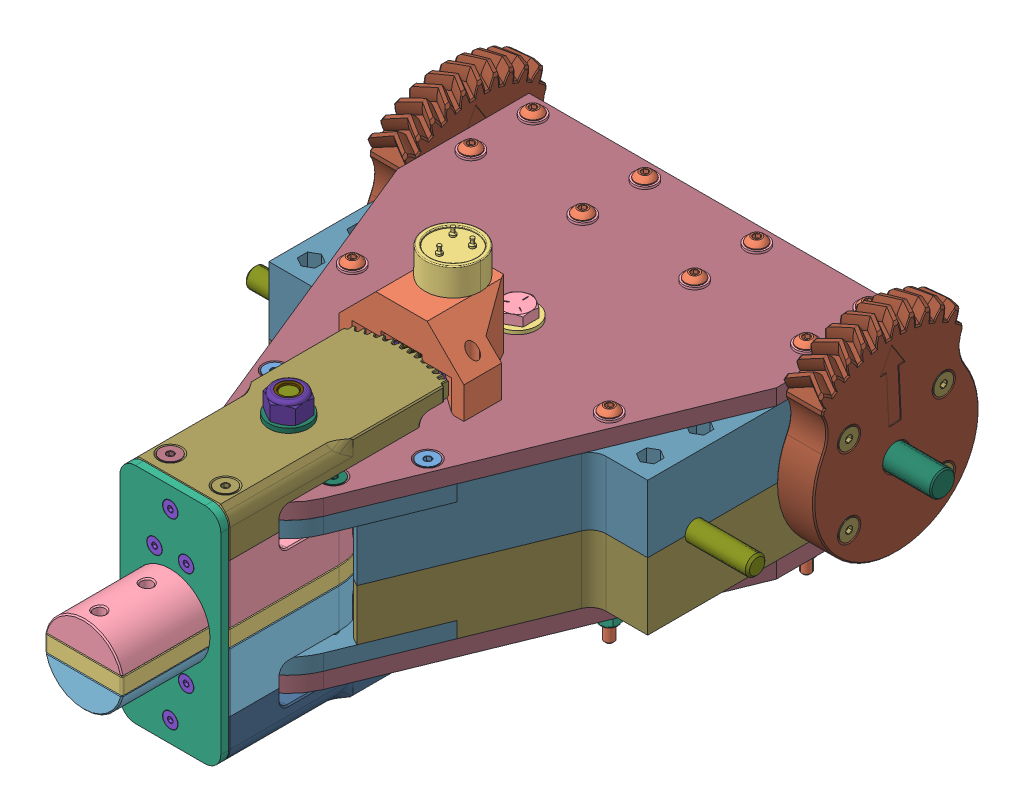
SolidWorks assembly Stick Roll Axis Box Assembly, configuration Default. Lengths in mm.
Overall size (220 126.88 270.74).
294 component instances, 60 part files, 4 mates.
Components (placement in the parent):
- Scissor Arm A Asmbly-1: Scissor Arm A Asmbly [Default] at origin size (38.52 47.7 135.26)
  - Scissor Arm A Link-1: Scissor Arm A Link [Default] at origin size (38.52 3.17 135.26)
  - Scissor Arm A Block-1: Scissor Arm A Block [Default] at origin size (16.74 30.53 64.54)
  - Scissor Arm A Link-2: Scissor Arm A Link [Default] at (0 33.7 0) size (38.52 3.17 135.26)
  - Scissor Cushion-1: Scissor Cushion [Default] at origin size (3.55 36.88 24.93)
  - 93475A230-1: 93475A230 [Default] at (12.7 -18.4375 108.6134) x (1 0 0) z (0 -1 0) size (9 9 0.9)
  - 93475A230-2: 93475A230 [Default] at (17.34 -18.4375 56.0398) x (1 0 0) z (0 -1 0) size (9 9 0.9)
  - 93475A230-3: 93475A230 [Default] at (17.34 -19.3375 56.0398) x (1 0 0) z (0 -1 0) size (9 9 0.9)
  - 93475A230-4: 93475A230 [Default] at (12.7 -19.3375 108.6134) x (1 0 0) z (0 -1 0) size (9 9 0.9)
  - 92095A205-1: 92095A205 [Default] at (12.7 -22.4375 108.6134) x (1 0 0) z (0 -1 0) size (7.65 7.69 47.7)
  - 92095A205-2: 92095A205 [Default] at (17.34 -22.4375 56.0398) x (1 0 0) z (0 -1 0) size (7.65 7.69 47.7)
  - 93475A230-5: 93475A230 [Default] at (12.7 18.4375 108.6134) x (1 0 0) z (0 1 0) size (9 9 0.9)
  - 93475A230-6: 93475A230 [Default] at (17.34 18.4375 56.0398) x (1 0 0) z (0 1 0) size (9 9 0.9)
  - 93625A150-1: 93625A150 [Default] at (12.7 19.3375 108.6134) x (1 0 0) z (0 1 0) size (7 8.08 5)
    - 93625A150_2-1: 93625A150_2 [Default] at origin size (7 8.08 5)
    - 93625A150-1: 93625A150 [Default] at origin size (6.53 6.53 0.53)
  - 93625A150-2: 93625A150 [Default] at (17.34 19.3375 56.0398) x (1 0 0) z (0 1 0) size (7 8.08 5)
    - 93625A150_2-1: 93625A150_2 [Default] at origin size (7 8.08 5)
    - 93625A150-1: 93625A150 [Default] at origin size (6.53 6.53 0.53)
- Scissor Arm B Asmbly-1: Scissor Arm B Asmbly [Default] at origin size (38.52 47.7 135.26)
  - Scissor Arm B Link Upper-1: Scissor Arm B Link Upper [Default] at origin size (37.06 3.18 116.32)
  - Scissor Arm B Link Spacer-1: Scissor Arm B Link Spacer [Default] at origin size (16.74 2.2 64.54)
  - Scissor Arm B Link Lower-1: Scissor Arm B Link Lower [Default] at origin size (18.2 3.18 83.47)
  - Scissor Arm B Block-1: Scissor Arm B Block [Default] at origin size (16.74 19.78 64.54)
  - Scissor Arm B Link Lower-2: Scissor Arm B Link Lower [Default] at (0 33.7 0) size (18.2 3.18 83.47)
  - Scissor Arm B Link Spacer-2: Scissor Arm B Link Spacer [Default] at (0 28.325 0) size (16.74 2.2 64.54)
  - Scissor Arm B Link Upper-2: Scissor Arm B Link Upper [Default] at (0 22.95 0) size (37.06 3.18 116.32)
  - Scissor Cushion-1: Scissor Cushion [Default] x (-1 0 0) z (0 0 1) size (3.55 36.88 24.93)
  - 93475A230-1: 93475A230 [Default] at (-12.7 -18.4375 108.6134) x (1 0 0) z (0 -1 0) size (9 9 0.9)
  - 93475A230-2: 93475A230 [Default] at (-17.34 -18.4375 56.0398) x (1 0 0) z (0 -1 0) size (9 9 0.9)
  - 93475A230-3: 93475A230 [Default] at (-12.7 -19.3375 108.6134) x (1 0 0) z (0 -1 0) size (9 9 0.9)
  - 93475A230-4: 93475A230 [Default] at (-17.34 -19.3375 56.0398) x (1 0 0) z (0 -1 0) size (9 9 0.9)
  - 92095A205-1: 92095A205 [Default] at (-12.7 -22.4375 108.6134) x (1 0 0) z (0 -1 0) size (7.65 7.69 47.7)
  - 92095A205-2: 92095A205 [Default] at (-17.34 -22.4375 56.0398) x (1 0 0) z (0 -1 0) size (7.65 7.69 47.7)
  - 93475A230-5: 93475A230 [Default] at (-17.34 18.4375 56.0398) x (1 0 0) z (0 1 0) size (9 9 0.9)
  - 93475A230-6: 93475A230 [Default] at (-12.7 18.4375 108.6134) x (1 0 0) z (0 1 0) size (9 9 0.9)
  - 93625A150-1: 93625A150 [Default] at (-17.34 19.3375 56.0398) x (1 0 0) z (0 1 0) size (7 8.08 5)
    - 93625A150_2-1: 93625A150_2 [Default] at origin size (7 8.08 5)
    - 93625A150-1: 93625A150 [Default] at origin size (6.53 6.53 0.53)
  - 93625A150-2: 93625A150 [Default] at (-12.7 19.3375 108.6134) x (1 0 0) z (0 1 0) size (7 8.08 5)
    - 93625A150_2-1: 93625A150_2 [Default] at origin size (7 8.08 5)
    - 93625A150-1: 93625A150 [Default] at origin size (6.53 6.53 0.53)
- Main Casing Asmbly-1: Main Casing Asmbly [Default] at origin size (220 70.89 189.11)
  - Main Casing A Pre-Asmbly-1: Main Casing A Pre-Asmbly [Default] at (0 141.5449 -37.4581) x (1 0 0) z (0 -0.045363 0.998971) size (152.4 35.57 187.69)
    - Main Casing A-1: Main Casing A [Default] at (0 -139.7 43.8404) x (1 0 0) z (0 0.045363 0.998971) size (152.4 27.13 186.65)
    - 93625A150-1: 93625A150 [Default] at (30.8014 -142.8781 172.2532) x (0.927184 0.016993 0.374221) z (0 0.998971 -0.045363) size (7 8.08 5)
      - 93625A150_2-1: 93625A150_2 [Default] at origin size (7 8.08 5)
      - 93625A150-1: 93625A150 [Default] at origin size (6.53 6.53 0.53)
    - 93625A150-2: 93625A150 [Default] at (-30.8014 -142.8781 172.2532) x (0.927184 -0.016993 -0.374221) z (0 0.998971 -0.045363) size (7 8.08 5)
      - 93625A150_2-1: 93625A150_2 [Default] at origin size (7 8.08 5)
      - 93625A150-1: 93625A150 [Default] at origin size (6.53 6.53 0.53)
    - 94180A351-1: 94180A351 [Default] at (76.2 -154.6945 63.5909) x (0 0.045363 0.998971) z (1 0 0) size (6.35 6.35 4.7)
    - 94180A351-2: 94180A351 [Default] at (76.2 -156.4228 25.5301) x (0 0.045363 0.998971) z (1 0 0) size (6.35 6.35 4.7)
    - 94180A351-3: 94180A351 [Default] at (-76.2 -154.6945 63.5909) x (0 -0.045363 -0.998971) z (-1 0 0) size (6.35 6.35 4.7)
    - 94180A351-4: 94180A351 [Default] at (-76.2 -156.4228 25.5301) x (0 -0.045363 -0.998971) z (-1 0 0) size (6.35 6.35 4.7)
  - Main Casing B Pre-Asmbly-1: Main Casing B Pre-Asmbly [Default] at (0 141.5449 -37.4581) x (1 0 0) z (0 -0.045363 0.998971) size (152.4 35.57 187.69)
    - Main Casing B-1: Main Casing B [Default] at (0 -139.7 43.8404) x (1 0 0) z (0 0.045363 0.998971) size (152.4 27.13 186.65)
    - 93625A150-1: 93625A150 [Default] at (-30.8014 -124.8966 171.4366) x (0.927184 -0.016993 -0.374221) z (0 -0.998971 0.045363) size (7 8.08 5)
      - 93625A150_2-1: 93625A150_2 [Default] at origin size (7 8.08 5)
      - 93625A150-1: 93625A150 [Default] at origin size (6.53 6.53 0.53)
    - 93625A150-2: 93625A150 [Default] at (30.8014 -124.8966 171.4366) x (0.927184 0.016993 0.374221) z (0 -0.998971 0.045363) size (7 8.08 5)
      - 93625A150_2-1: 93625A150_2 [Default] at origin size (7 8.08 5)
      - 93625A150-1: 93625A150 [Default] at origin size (6.53 6.53 0.53)
    - 93625A150-3: 93625A150 [Default] at (26.018 -120.7292 183.0242) x (0.927184 0.016993 0.374221) z (0 0.998971 -0.045363) size (7 8.08 5)
      - 93625A150_2-1: 93625A150_2 [Default] at origin size (7 8.08 5)
      - 93625A150-1: 93625A150 [Default] at origin size (6.53 6.53 0.53)
    - 93625A150-4: 93625A150 [Default] at (-26.018 -120.7292 183.0242) x (0.927184 -0.016993 -0.374221) z (0 0.998971 -0.045363) size (7 8.08 5)
      - 93625A150_2-1: 93625A150_2 [Default] at origin size (7 8.08 5)
      - 93625A150-1: 93625A150 [Default] at origin size (6.53 6.53 0.53)
    - 93625A150-5: 93625A150 [Default] at (-68.2 -128.2463 119.4387) x (1 0 0) z (0 0.998971 -0.045363) size (7 8.08 5)
      - 93625A150_2-1: 93625A150_2 [Default] at origin size (7 8.08 5)
      - 93625A150-1: 93625A150 [Default] at origin size (6.53 6.53 0.53)
    - 93625A150-6: 93625A150 [Default] at (-68.2 -129.1536 99.4592) x (1 0 0) z (0 0.998971 -0.045363) size (7 8.08 5)
      - 93625A150_2-1: 93625A150_2 [Default] at origin size (7 8.08 5)
      - 93625A150-1: 93625A150 [Default] at origin size (6.53 6.53 0.53)
    - 93625A150-7: 93625A150 [Default] at (68.2 -128.2463 119.4387) x (1 0 0) z (0 0.998971 -0.045363) size (7 8.08 5)
      - 93625A150_2-1: 93625A150_2 [Default] at origin size (7 8.08 5)
      - 93625A150-1: 93625A150 [Default] at origin size (6.53 6.53 0.53)
    - 93625A150-8: 93625A150 [Default] at (68.2 -129.1536 99.4592) x (1 0 0) z (0 0.998971 -0.045363) size (7 8.08 5)
      - 93625A150_2-1: 93625A150_2 [Default] at origin size (7 8.08 5)
      - 93625A150-1: 93625A150 [Default] at origin size (6.53 6.53 0.53)
    - 94180A351-1: 94180A351 [Default] at (-76.2 -122.9772 62.1507) x (0 -0.045363 -0.998971) z (-1 0 0) size (6.35 6.35 4.7)
    - 94180A351-2: 94180A351 [Default] at (-76.2 -124.7055 24.0899) x (0 -0.045363 -0.998971) z (-1 0 0) size (6.35 6.35 4.7)
    - 94180A351-3: 94180A351 [Default] at (76.2 -122.9772 62.1507) x (0 0.045363 0.998971) z (1 0 0) size (6.35 6.35 4.7)
    - 94180A351-4: 94180A351 [Default] at (76.2 -124.7055 24.0899) x (0 0.045363 0.998971) z (1 0 0) size (6.35 6.35 4.7)
  - Pitch Axis Rod-1: Pitch Axis Rod [Default] at origin size (220 10 10)
  - 91310A544-1: 91310A544 [Default] at (56.2 0 66.04) x (0 0 1) z (-1 0 0) size (13 15.01 50.3)
  - 91310A544-2: 91310A544 [Default] at (-56.2 0 66.04) x (0 0 -1) z (1 0 0) size (13 15.01 50.3)
  - 57485K68-1: 57485K68 [Default] at (49.45 0 0) x (0 1 0) z (-1 0 0) size (22 22 10)
    - 57485K68-1: 57485K68 [Default] at origin size (22 22 10)
    - 57485K68_2-1: 57485K68_2 [Default] at origin size (4.9 5 4.9)
  - 57485K68-2: 57485K68 [Default] at (-39.45 0 0) x (0 1 0) z (-1 0 0) size (22 22 10)
    - 57485K68-1: 57485K68 [Default] at origin size (22 22 10)
    - 57485K68_2-1: 57485K68_2 [Default] at origin size (4.9 5 4.9)
  - 57485K68-3: 57485K68 [Default] at (5 0 0) x (0 1 0) z (-1 0 0) size (22 22 10)
    - 57485K68-1: 57485K68 [Default] at origin size (22 22 10)
    - 57485K68_2-1: 57485K68_2 [Default] at origin size (4.9 5 4.9)
  - 91390A121-1: 91390A121 [Default] at (44.45 0 -9.9396) x (1 0 0) z (0 0 -1) size (4.9 4.9 10.14)
  - 91390A121-2: 91390A121 [Default] at (-44.45 0 -9.9396) x (1 0 0) z (0 0 -1) size (4.9 4.9 10.14)
  - 91390A121-3: 91390A121 [Default] at (0 0 -9.9396) x (1 0 0) z (0 0 -1) size (4.9 4.9 10.14)
  - 92125A205-1: 92125A205 [Default] at (-68.2 -26.9875 76.04) x (1 0 0) z (0 -1 0) size (8 8 40.14)
  - 92125A205-2: 92125A205 [Default] at (-68.2 -26.9875 56.04) x (1 0 0) z (0 -1 0) size (8 8 40.14)
  - 92125A205-3: 92125A205 [Default] at (68.2 -26.9875 76.04) x (1 0 0) z (0 -1 0) size (8 8 40.14)
  - 92125A205-4: 92125A205 [Default] at (68.2 -26.9875 56.04) x (1 0 0) z (0 -1 0) size (8 8 40.14)
  - 92125A205-5: 92125A205 [Default] at (-26.018 -20.6375 139.9011) x (1 0 0) z (0 -1 0) size (8 8 40.14)
  - 92125A205-6: 92125A205 [Default] at (26.018 -20.6375 139.9011) x (1 0 0) z (0 -1 0) size (8 8 40.14)
- Pivoting Assembly-1: Pivoting Assembly [Default] at origin size (42.82 89.97 158.75)
  - Pivot Mid Plate-1: Pivot Mid Plate [Default] at origin size (40.64 6.35 158.75)
  - Pivot Block A-1: Pivot Block A [Default] at origin size (41.73 24.41 158.75)
  - Pivot Block B-1: Pivot Block B [Default] at origin size (41.73 24.41 158.75)
  - Pivot Top Plate-1: Pivot Top Plate [Default] at origin size (40.64 89.97 3.17)
  - 94180A331-1: 94180A331 [Default] at (-6.35 -20.8575 197.7644) size (5.56 5.56 3.8)
  - 94180A331-2: 94180A331 [Default] at (6.35 -20.8575 197.7644) size (5.56 5.56 3.8)
  - 94180A331-3: 94180A331 [Default] at (-6.35 20.8575 197.7644) size (5.56 5.56 3.8)
  - 94180A331-4: 94180A331 [Default] at (6.35 20.8575 197.7644) size (5.56 5.56 3.8)
  - 91294A130-1: 91294A130 [Default] at (-6.35 -20.8575 200.9394) size (6 6 10.12)
  - 91294A130-2: 91294A130 [Default] at (6.35 -20.8575 200.9394) size (6 6 10.12)
  - 91294A130-3: 91294A130 [Default] at (-6.35 20.8575 200.9394) size (6 6 10.12)
  - 91294A130-4: 91294A130 [Default] at (6.35 20.8575 200.9394) size (6 6 10.12)
  - 94180A351-1: 94180A351 [Default] at (-11.1125 -27.2075 189.8269) x (1 0 0) z (0 -1 0) size (6.35 6.35 4.7)
  - 94180A351-2: 94180A351 [Default] at (11.1125 27.2075 189.8269) x (1 0 0) z (0 1 0) size (6.35 6.35 4.7)
  - 93625A150-1: 93625A150 [Default] at (-11.1125 -3.175 189.8269) x (1 0 0) z (0 -1 0) size (7 8.08 5)
    - 93625A150_2-1: 93625A150_2 [Default] at origin size (7 8.08 5)
    - 93625A150-1: 93625A150 [Default] at origin size (6.53 6.53 0.53)
  - 93625A150-2: 93625A150 [Default] at (11.1125 3.175 189.8269) x (1 0 0) z (0 1 0) size (7 8.08 5)
    - 93625A150_2-1: 93625A150_2 [Default] at origin size (7 8.08 5)
    - 93625A150-1: 93625A150 [Default] at origin size (6.53 6.53 0.53)
  - 93625A150-3: 93625A150 [Default] at (-11.1125 -9.8438 170.7769) x (1 0 0) z (0 -1 0) size (7 8.08 5)
    - 93625A150_2-1: 93625A150_2 [Default] at origin size (7 8.08 5)
    - 93625A150-1: 93625A150 [Default] at origin size (6.53 6.53 0.53)
  - 93625A150-4: 93625A150 [Default] at (11.1125 -9.8438 170.7769) x (1 0 0) z (0 -1 0) size (7 8.08 5)
    - 93625A150_2-1: 93625A150_2 [Default] at origin size (7 8.08 5)
    - 93625A150-1: 93625A150 [Default] at origin size (6.53 6.53 0.53)
  - 92125A204-1: 92125A204 [Default] at (11.1125 19.8438 170.7769) x (1 0 0) z (0 1 0) size (8 8 35.14)
  - 92125A204-2: 92125A204 [Default] at (-11.1125 19.8438 170.7769) x (1 0 0) z (0 1 0) size (8 8 35.14)
- Roll Damper Arm A Asmbly-1: Roll Damper Arm A Asmbly [Default] at (0 141.5449 -37.4581) x (1 0 0) z (0 -0.045363 0.998971) size (44.3 24.94 94.29)
  - Roll Damper Arm A-1: Roll Damper Arm A [Default] at (0 -177.6864 199.0377) x (-1 0 0) z (0 0.998971 -0.045363) size (44.3 93.45 20.73)
  - 94180A502-1: 94180A502 [Default] at (0 -167.4235 243.0675) x (-1 0 0) z (0 0.045363 0.998971) size (5.56 5.56 3.81)
- Roll Damper Arm B Asmbly-1: Roll Damper Arm B Asmbly [Default] at (0 44.9875 153.3144) x (1 0 0) z (0 -1 0) size (44.3 93.45 20.73)
  - Roll Damper Arm B-1: Roll Damper Arm B [Default] at origin size (44.3 93.45 20.73)
  - 94180A502-1: 94180A502 [Default] at (0 44.45 8.255) x (1 0 0) z (0 1 0) size (5.56 5.56 3.81)
- Fwd Plate Assembly-1: Fwd Plate Assembly [Default] at origin size (152.4 23.35 210.99)
  - Main Plate Sub Asmbly-1: Main Plate Sub Asmbly [Default] at origin size (152.4 12.84 210.99)
    - Main Plate-1: Main Plate [Default] at origin size (152.4 6.35 210.99)
    - Bearing Plate-1: Bearing Plate [Default] at origin size (78.15 6.35 60.33)
    - 91294A192 - M4 x 0.7 mm, 12 mm Long Hex Drive Flat Head Screw-1: 91294A192 - M4 x 0.7 mm, 12 mm Long Hex Drive Flat Head Screw [Default] at (0 -33.3375 171.3144) x (1 0 0) z (0 -1 0) size (8 8 12.14)
    - 91294A192 - M4 x 0.7 mm, 12 mm Long Hex Drive Flat Head Screw-2: 91294A192 - M4 x 0.7 mm, 12 mm Long Hex Drive Flat Head Screw [Default] at (-18 -33.3375 153.3144) x (1 0 0) z (0 -1 0) size (8 8 12.14)
    - 91294A192 - M4 x 0.7 mm, 12 mm Long Hex Drive Flat Head Screw-3: 91294A192 - M4 x 0.7 mm, 12 mm Long Hex Drive Flat Head Screw [Default] at (18 -33.3375 153.3144) x (1 0 0) z (0 -1 0) size (8 8 12.14)
    - 8x22x7+Bearing+-+6082Z-8x22x7_6082Z-8x22x7-1: 8x22x7+Bearing+-+6082Z-8x22x7_6082Z-8x22x7 [Default] at (0 -29.8375 153.3144) x (1 0 0) z (0 -1 0) size (22 22 7.01)
  - FRT-D2-152-G1-1: FRT-D2-152-G1 [Default] at (0 -24.9875 99.3144) x (1 0 0) z (0 -1 0) size (50 25 19)
    - FRT-D2-152-1: FRT-D2-152 [Default] at origin size (50 25 19)
    - FRT-D2-G1 12mm Gear-1: FRT-D2-G1 12mm Gear [Default] at (0 0 14) x (0 -1 0) z (0 0 1) size (14 14 5)
  - 93475A230-1: 93475A230 [Default] at (-20 -33.3375 99.3144) x (1 0 0) z (0 -1 0) size (9 9 0.9)
  - 93475A230-2: 93475A230 [Default] at (20 -33.3375 99.3144) x (1 0 0) z (0 -1 0) size (9 9 0.9)
  - 93625A150-1: 93625A150 [Default] at (-20 -34.2375 99.3144) x (1 0 0) z (0 -1 0) size (7 8.08 5)
    - 93625A150_2-1: 93625A150_2 [Default] at origin size (7 8.08 5)
    - 93625A150-1: 93625A150 [Default] at origin size (6.53 6.53 0.53)
  - 93625A150-2: 93625A150 [Default] at (20 -34.2375 99.3144) x (1 0 0) z (0 -1 0) size (7 8.08 5)
    - 93625A150_2-1: 93625A150_2 [Default] at origin size (7 8.08 5)
    - 93625A150-1: 93625A150 [Default] at origin size (6.53 6.53 0.53)
  - 91239A150-1: 91239A150 [Default] at (20 -22.7875 99.3144) x (1 0 0) z (0 1 0) size (7.65 7.69 18.7)
  - 91239A150-2: 91239A150 [Default] at (-20 -22.7875 99.3144) x (1 0 0) z (0 1 0) size (7.65 7.69 18.7)
- Aft Plate Assembly-1: Aft Plate Assembly [Default] x (-1 0 0) z (0 0 1) size (152.4 54.07 210.99)
  - Main Plate Sub Asmbly_1-1: Main Plate Sub Asmbly_1 [Default] at origin size (152.4 12.84 210.99)
    - Main Plate-1: Main Plate [Default] at origin size (152.4 6.35 210.99)
    - Bearing Plate-1: Bearing Plate [Default] at origin size (78.15 6.35 60.33)
    - 91294A192 - M4 x 0.7 mm, 12 mm Long Hex Drive Flat Head Screw-1: 91294A192 - M4 x 0.7 mm, 12 mm Long Hex Drive Flat Head Screw [Default] at (0 -33.3375 171.3144) x (1 0 0) z (0 -1 0) size (8 8 12.14)
    - 91294A192 - M4 x 0.7 mm, 12 mm Long Hex Drive Flat Head Screw-2: 91294A192 - M4 x 0.7 mm, 12 mm Long Hex Drive Flat Head Screw [Default] at (-18 -33.3375 153.3144) x (1 0 0) z (0 -1 0) size (8 8 12.14)
    - 91294A192 - M4 x 0.7 mm, 12 mm Long Hex Drive Flat Head Screw-3: 91294A192 - M4 x 0.7 mm, 12 mm Long Hex Drive Flat Head Screw [Default] at (18 -33.3375 153.3144) x (1 0 0) z (0 -1 0) size (8 8 12.14)
    - 8x22x7+Bearing+-+6082Z-8x22x7_6082Z-8x22x7-1: 8x22x7+Bearing+-+6082Z-8x22x7_6082Z-8x22x7 [Default] at (0 -29.8375 153.3144) x (1 0 0) z (0 -1 0) size (22 22 7.01)
  - FRT-D2-152-G1_1-1: FRT-D2-152-G1_1 [Default] at (0 -24.9875 99.3144) x (-1 0 0) z (0 -1 0) size (50 25 19)
    - FRT-D2-152-1: FRT-D2-152 [Default] at origin size (50 25 19)
    - FRT-D2-G1 12mm Gear-2: FRT-D2-G1 12mm Gear [Default] at (0 0 14) x (0 -1 0) z (0 0 1) size (14 14 5)
  - 91239A150-1: 91239A150 [Default] at (20 -22.7875 99.3144) x (-1 0 0) z (0 1 0) size (7.65 7.69 18.7)
  - 91239A150-2: 91239A150 [Default] at (-20 -22.7875 99.3144) x (-1 0 0) z (0 1 0) size (7.65 7.69 18.7)
  - Roll Sensor Asmbly-1: Roll Sensor Asmbly [Default] x (-1 0 0) z (0 0 1) size (50.16 41.37 31.85)
    - Roll Sensor Mount Main-1: Roll Sensor Mount Main [Default] at origin size (50.16 27.53 31.75)
    - 94180A351-1: 94180A351 [Default] at (-20 33.3375 99.3144) x (1 0 0) z (0 -1 0) size (6.35 6.35 4.7)
    - 94180A351-2: 94180A351 [Default] at (20 33.3375 99.3144) x (1 0 0) z (0 -1 0) size (6.35 6.35 4.7)
    - 6127V1AxxxL.5FS-1: 6127V1AxxxL.5FS [6127V1A360L.5FS] at (0 61.2423 87.3281) x (1 0 0) z (0 0.011977 0.999928) size (22.23 35.66 22.23)
    - Roll Damper Gear-1: Roll Damper Gear [Default] at (0 38.9173 87.5956) x (-1 0 0) z (0 0.999928 -0.011977) size (14 14 10)
- Scissor Stop-1: Scissor Stop [Default] at origin size (20.44 53.98 22.23)
- 93475A240-1: 93475A240 [Default] at (-19.471 -18.4375 37.1094) x (1 0 0) z (0 -1 0) size (10 10 1.1)
- 93475A240-2: 93475A240 [Default] at (19.471 -18.4375 37.1094) x (1 0 0) z (0 -1 0) size (10 10 1.1)
- 93475A240-3: 93475A240 [Default] at (-19.471 19.5375 37.1094) x (1 0 0) z (0 -1 0) size (10 10 1.1)
- 93475A240-4: 93475A240 [Default] at (19.471 18.4375 37.1094) x (1 0 0) z (0 1 0) size (10 10 1.1)
- 91239A244-1: 91239A244 [Default] at (-19.471 -22.2875 37.1094) x (1 0 0) z (0 -1 0) size (9.57 9.61 48.38)
- 91239A244-2: 91239A244 [Default] at (19.471 -22.2875 37.1094) x (1 0 0) z (0 -1 0) size (9.57 9.61 48.38)
- 93625A200 - M5 x 0.8 mm Nylon-Insert Locknut-1: 93625A200 - M5 x 0.8 mm Nylon-Insert Locknut [Default] at (19.471 19.5375 37.1094) x (1 0 0) z (0 1 0) size (8 9.24 5)
  - 93625A200 - M5 x 0.8 mm Nylon-Insert Locknut_2-1: 93625A200 - M5 x 0.8 mm Nylon-Insert Locknut_2 [Default] at origin size (8 9.24 5)
  - 93625A200 - M5 x 0.8 mm Nylon-Insert Locknut-1: 93625A200 - M5 x 0.8 mm Nylon-Insert Locknut [Default] at origin size (7.53 7.53 0.53)
- 93625A200 - M5 x 0.8 mm Nylon-Insert Locknut-2: 93625A200 - M5 x 0.8 mm Nylon-Insert Locknut [Default] at (-19.471 19.5375 37.1094) x (1 0 0) z (0 1 0) size (8 9.24 5)
  - 93625A200 - M5 x 0.8 mm Nylon-Insert Locknut_2-1: 93625A200 - M5 x 0.8 mm Nylon-Insert Locknut_2 [Default] at origin size (8 9.24 5)
  - 93625A200 - M5 x 0.8 mm Nylon-Insert Locknut-1: 93625A200 - M5 x 0.8 mm Nylon-Insert Locknut [Default] at origin size (7.53 7.53 0.53)
- 9654K421 - 1.75 Long, 0.5_ OD, 0.055_ WD Steel Extension Spring with_ Loop Ends-1: 9654K421 - 1.75 Long, 0.5_ OD, 0.055_ WD Steel Extension Spring with_ Loop Ends [Default] at (-1.096 0.0125 37.1094) x (1 0 0) z (0 -1 0) size (44.45 14.38 14.38)
- 9654K421 - 1.75 Long, 0.5_ OD, 0.055_ WD Steel Extension Spring with_ Loop Ends-2: 9654K421 - 1.75 Long, 0.5_ OD, 0.055_ WD Steel Extension Spring with_ Loop Ends [Default] at (-1.096 -13.9375 37.1094) x (1 0 0) z (0 -1 0) size (44.45 14.38 14.38)
- 9654K421 - 1.75 Long, 0.5_ OD, 0.055_ WD Steel Extension Spring with_ Loop Ends-3: 9654K421 - 1.75 Long, 0.5_ OD, 0.055_ WD Steel Extension Spring with_ Loop Ends [Default] at (-1.096 13.9625 37.1094) x (1 0 0) z (0 -1 0) size (44.45 14.38 14.38)
- Pitch Damper Gear Large-1: Pitch Damper Gear Large [Default] at (-83.7 0 0) x (0 0.99889 0.047106) z (1 0 0) size (80.38 66.68 15)
- Pitch Damper Gear Large-2: Pitch Damper Gear Large [Default] at (83.7 0 0) x (0 0.99889 0.047106) z (1 0 0) size (80.38 66.68 15)
- 91294A198-1: 91294A198 [Default] at (91.2 -15.9082 19.0223) x (0 -0.047106 0.99889) z (1 0 0) size (8 8 25.14)
- 91294A198-2: 91294A198 [Default] at (91.2 15.9082 -19.0223) x (0 -0.047106 0.99889) z (1 0 0) size (8 8 25.14)
- 91294A198-3: 91294A198 [Default] at (91.2 -15.8417 -19.0777) x (0 -0.047106 0.99889) z (1 0 0) size (8 8 25.14)
- 91294A198-4: 91294A198 [Default] at (91.2 15.8417 19.0777) x (0 0.047106 -0.99889) z (1 0 0) size (8 8 25.14)
- 91294A198-5: 91294A198 [Default] at (-91.2 15.8417 19.0777) x (0 0.047106 -0.99889) z (-1 0 0) size (8 8 25.14)
- 91294A198-6: 91294A198 [Default] at (-91.2 -15.8417 -19.0777) x (0 0.047106 -0.99889) z (-1 0 0) size (8 8 25.14)
- 91294A198-7: 91294A198 [Default] at (-91.2 15.9082 -19.0223) x (0 0.047106 -0.99889) z (-1 0 0) size (8 8 25.14)
- 91294A198-8: 91294A198 [Default] at (-91.2 -15.9082 19.0223) x (0 0.047106 -0.99889) z (-1 0 0) size (8 8 25.14)
- 92125A373-1: 92125A373 [Default] at (-11.1125 44.9875 189.8269) x (1 0 0) z (0 1 0) size (8 8 55.09)
- 92125A373-2: 92125A373 [Default] at (11.1125 -44.9875 189.8269) x (1 0 0) z (0 -1 0) size (8 8 55.09)
- 91294A198-9: 91294A198 [Default] at (-11.1125 -44.9875 189.8269) x (1 0 0) z (0 -1 0) size (8 8 25.14)
- 91294A198-10: 91294A198 [Default] at (11.1125 44.9875 189.8269) x (1 0 0) z (0 1 0) size (8 8 25.14)
- 95630A670-1: 95630A670 [Default] at (0 -7.6875 153.3144) x (1 0 0) z (0 -1 0) size (18 18 2.2)
- 95630A670-2: 95630A670 [Default] at (0 -13.0625 153.3144) x (1 0 0) z (0 -1 0) size (18 18 2.2)
- 95630A670-3: 95630A670 [Default] at (0 7.6875 153.3144) x (1 0 0) z (0 1 0) size (18 18 2.2)
- 95630A670-4: 95630A670 [Default] at (0 13.0625 153.3144) x (1 0 0) z (0 1 0) size (18 18 2.2)
- 93475A270 - M8 Stainless Steel Washer-1: 93475A270 - M8 Stainless Steel Washer [Default] at (0 34.9875 153.3144) x (1 0 0) z (0 -1 0) size (16 16 1.8)
- 93475A270 - M8 Stainless Steel Washer-2: 93475A270 - M8 Stainless Steel Washer [Default] at (0 -34.9875 153.3144) x (1 0 0) z (0 1 0) size (16 16 1.8)
- 91280A174-1: 91280A174 [Default] at (0 -40.9875 153.3144) x (1 0 0) z (0 -1 0) size (13 15.01 100.3)
- 93475A270 - M8 Stainless Steel Washer-3: 93475A270 - M8 Stainless Steel Washer [Default] at (0 46.7875 153.3144) x (1 0 0) z (0 -1 0) size (16 16 1.8)
- 90576A117 - M8 x 1.25mm Nylon-Insert Lock Nut-1: 90576A117 - M8 x 1.25mm Nylon-Insert Lock Nut [Default] at (0 46.7875 153.3144) x (1 0 0) z (0 1 0) size (13 15.01 8)
  - 90576A117 - M8 x 1.25mm Nylon-Insert Lock Nut_2-1: 90576A117 - M8 x 1.25mm Nylon-Insert Lock Nut_2 [Default] at origin size (13 15.01 8)
  - 90576A117 - M8 x 1.25mm Nylon-Insert Lock Nut-1: 90576A117 - M8 x 1.25mm Nylon-Insert Lock Nut [Default] at origin size (12.54 12.54 1.03)
- 91294A130-1: 91294A130 [Default] at (0 -36.7325 200.9394) size (6 6 10.12)
- 91294A130-2: 91294A130 [Default] at (0 36.7325 200.9394) size (6 6 10.12)
- 92125A203-1: 92125A203 [Default] at (-30.8014 33.3375 128.1364) x (1 0 0) z (0 1 0) size (8 8 30.14)
- 92125A203-2: 92125A203 [Default] at (-30.8014 -33.3375 128.1364) x (1 0 0) z (0 -1 0) size (8 8 30.14)
- 92125A203-3: 92125A203 [Default] at (30.8014 -33.3375 128.1364) x (1 0 0) z (0 -1 0) size (8 8 30.14)
- 92125A203-4: 92125A203 [Default] at (30.8014 33.3375 128.1364) x (1 0 0) z (0 1 0) size (8 8 30.14)
- 93475A230-1: 93475A230 [Default] at (67.5 33.3375 12.5) x (1 0 0) z (0 1 0) size (9 9 0.9)
- 93475A230-2: 93475A230 [Default] at (67.5 33.3375 -12.5) x (1 0 0) z (0 1 0) size (9 9 0.9)
- 93475A230-3: 93475A230 [Default] at (22.5 33.3375 12.5) x (1 0 0) z (0 1 0) size (9 9 0.9)
- 93475A230-4: 93475A230 [Default] at (22.5 33.3375 -12.5) x (1 0 0) z (0 1 0) size (9 9 0.9)
- 93475A230-5: 93475A230 [Default] at (-22.5 33.3375 12.5) x (1 0 0) z (0 1 0) size (9 9 0.9)
- 93475A230-6: 93475A230 [Default] at (-22.5 33.3375 -12.5) x (1 0 0) z (0 1 0) size (9 9 0.9)
- 93475A230-7: 93475A230 [Default] at (-67.5 33.3375 12.5) x (1 0 0) z (0 1 0) size (9 9 0.9)
- 93475A230-8: 93475A230 [Default] at (-67.5 33.3375 -12.5) x (1 0 0) z (0 1 0) size (9 9 0.9)
- 93475A230-9: 93475A230 [Default] at (51.7 33.3375 76.04) x (1 0 0) z (0 1 0) size (9 9 0.9)
- 93475A230-10: 93475A230 [Default] at (-51.7 33.3375 76.04) x (1 0 0) z (0 1 0) size (9 9 0.9)
- 93475A230-11: 93475A230 [Default] at (-51.7 -34.2375 76.04) x (1 0 0) z (0 1 0) size (9 9 0.9)
- 93475A230-12: 93475A230 [Default] at (67.5 -34.2375 -12.5) x (1 0 0) z (0 1 0) size (9 9 0.9)
- 93475A230-13: 93475A230 [Default] at (51.7 -34.2375 76.04) x (1 0 0) z (0 1 0) size (9 9 0.9)
- 93475A230-14: 93475A230 [Default] at (67.5 -34.2375 12.5) x (1 0 0) z (0 1 0) size (9 9 0.9)
- 93475A230-15: 93475A230 [Default] at (-22.5 -34.2375 12.5) x (1 0 0) z (0 1 0) size (9 9 0.9)
- 93475A230-16: 93475A230 [Default] at (22.5 -34.2375 12.5) x (1 0 0) z (0 1 0) size (9 9 0.9)
- 93475A230-17: 93475A230 [Default] at (22.5 -34.2375 -12.5) x (1 0 0) z (0 1 0) size (9 9 0.9)
- 93475A230-18: 93475A230 [Default] at (-22.5 -34.2375 -12.5) x (1 0 0) z (0 1 0) size (9 9 0.9)
- 93475A230-19: 93475A230 [Default] at (-67.5 -34.2375 -12.5) x (1 0 0) z (0 1 0) size (9 9 0.9)
- 93475A230-20: 93475A230 [Default] at (-67.5 -34.2375 12.5) x (1 0 0) z (0 1 0) size (9 9 0.9)
- 92095A173-1: 92095A173 [Default] at (67.5 34.2375 12.5) x (1 0 0) z (0 1 0) size (7.65 7.69 82.7)
- 92095A173-2: 92095A173 [Default] at (67.5 34.2375 -12.5) x (1 0 0) z (0 1 0) size (7.65 7.69 82.7)
- 92095A173-3: 92095A173 [Default] at (22.5 34.2375 -12.5) x (1 0 0) z (0 1 0) size (7.65 7.69 82.7)
- 92095A173-4: 92095A173 [Default] at (22.5 34.2375 12.5) x (1 0 0) z (0 1 0) size (7.65 7.69 82.7)
- 92095A173-5: 92095A173 [Default] at (-67.5 34.2375 12.5) x (1 0 0) z (0 1 0) size (7.65 7.69 82.7)
- 92095A173-6: 92095A173 [Default] at (-22.5 34.2375 -12.5) x (1 0 0) z (0 1 0) size (7.65 7.69 82.7)
- 92095A173-7: 92095A173 [Default] at (-67.5 34.2375 -12.5) x (1 0 0) z (0 1 0) size (7.65 7.69 82.7)
- 92095A173-8: 92095A173 [Default] at (-22.5 34.2375 12.5) x (1 0 0) z (0 1 0) size (7.65 7.69 82.7)
- 92095A173-9: 92095A173 [Default] at (51.7 34.2375 76.04) x (1 0 0) z (0 1 0) size (7.65 7.69 82.7)
- 92095A173-10: 92095A173 [Default] at (-51.7 34.2375 76.04) x (1 0 0) z (0 1 0) size (7.65 7.69 82.7)
- 93625A150-1: 93625A150 [Default] at (67.5 -34.2375 12.5) x (1 0 0) z (0 -1 0) size (7 8.08 5)
  - 93625A150_2-1: 93625A150_2 [Default] at origin size (7 8.08 5)
  - 93625A150-1: 93625A150 [Default] at origin size (6.53 6.53 0.53)
- 93625A150-2: 93625A150 [Default] at (67.5 -34.2375 -12.5) x (1 0 0) z (0 -1 0) size (7 8.08 5)
  - 93625A150_2-1: 93625A150_2 [Default] at origin size (7 8.08 5)
  - 93625A150-1: 93625A150 [Default] at origin size (6.53 6.53 0.53)
- 93625A150-3: 93625A150 [Default] at (22.5 -34.2375 -12.5) x (1 0 0) z (0 -1 0) size (7 8.08 5)
  - 93625A150_2-1: 93625A150_2 [Default] at origin size (7 8.08 5)
  - 93625A150-1: 93625A150 [Default] at origin size (6.53 6.53 0.53)
- 93625A150-4: 93625A150 [Default] at (22.5 -34.2375 12.5) x (1 0 0) z (0 -1 0) size (7 8.08 5)
  - 93625A150_2-1: 93625A150_2 [Default] at origin size (7 8.08 5)
  - 93625A150-1: 93625A150 [Default] at origin size (6.53 6.53 0.53)
- 93625A150-5: 93625A150 [Default] at (-67.5 -34.2375 12.5) x (1 0 0) z (0 -1 0) size (7 8.08 5)
  - 93625A150_2-1: 93625A150_2 [Default] at origin size (7 8.08 5)
  - 93625A150-1: 93625A150 [Default] at origin size (6.53 6.53 0.53)
- 93625A150-6: 93625A150 [Default] at (-67.5 -34.2375 -12.5) x (1 0 0) z (0 -1 0) size (7 8.08 5)
  - 93625A150_2-1: 93625A150_2 [Default] at origin size (7 8.08 5)
  - 93625A150-1: 93625A150 [Default] at origin size (6.53 6.53 0.53)
- 93625A150-7: 93625A150 [Default] at (-22.5 -34.2375 -12.5) x (1 0 0) z (0 -1 0) size (7 8.08 5)
  - 93625A150_2-1: 93625A150_2 [Default] at origin size (7 8.08 5)
  - 93625A150-1: 93625A150 [Default] at origin size (6.53 6.53 0.53)
- 93625A150-8: 93625A150 [Default] at (-22.5 -34.2375 12.5) x (1 0 0) z (0 -1 0) size (7 8.08 5)
  - 93625A150_2-1: 93625A150_2 [Default] at origin size (7 8.08 5)
  - 93625A150-1: 93625A150 [Default] at origin size (6.53 6.53 0.53)
- 93625A150-9: 93625A150 [Default] at (-51.7 -34.2375 76.04) x (1 0 0) z (0 -1 0) size (7 8.08 5)
  - 93625A150_2-1: 93625A150_2 [Default] at origin size (7 8.08 5)
  - 93625A150-1: 93625A150 [Default] at origin size (6.53 6.53 0.53)
- 93625A150-10: 93625A150 [Default] at (51.7 -34.2375 76.04) x (1 0 0) z (0 -1 0) size (7 8.08 5)
  - 93625A150_2-1: 93625A150_2 [Default] at origin size (7 8.08 5)
  - 93625A150-1: 93625A150 [Default] at origin size (6.53 6.53 0.53)
- 92141A029 - 1_4 0.281_ ID, 0.625_ OD Steel Flat Washer-1: 92141A029 - 1_4 0.281_ ID, 0.625_ OD Steel Flat Washer [Default] at (0 -33.3375 61.352) x (1 0 0) z (0 -1 0) size (15.88 15.88 1.45)
- 92141A029 - 1_4 0.281_ ID, 0.625_ OD Steel Flat Washer-2: 92141A029 - 1_4 0.281_ ID, 0.625_ OD Steel Flat Washer [Default] at (0 33.3375 61.352) x (1 0 0) z (0 1 0) size (15.88 15.88 1.45)
- 91247A555-1: 91247A555 [Default] at (0 34.7853 61.352) x (1 0 0) z (0 1 0) size (11.11 12.83 86.52)
- 95615A120-1: 95615A120 [Default] at (0 -34.7853 61.352) x (1 0 0) z (0 -1 0) size (11.11 12.83 7.94)
  - 95615A120-1: 95615A120 [Default] at origin size (11.11 12.83 7.94)
  - 95615A120_2-1: 95615A120_2 [Default] at origin size (10.65 10.65 1.02)
Mates (geometry in assembly coordinates):
- Concentric1: concentric aligned: cylinder of Pivoting Assembly-1/Pivot Block A-1 through (0 3.175 153.3144) axis (0 1 0) radius 4; cylinder of 95630A670-3 through (0 7.6875 153.3144) axis (0 1 0) radius 9
- Symmetric1: symmetric aligned: plane of Pivoting Assembly-1 through (0 0 0) normal (0 1 0); plane of Aft Plate Assembly-1/Main Plate Sub Asmbly_1-1/Main Plate-1 through (0 -33.3375 79.5712) normal (0 -1 0); plane of Fwd Plate Assembly-1/Main Plate Sub Asmbly-1/Main Plate-1 through (0 33.3375 79.5712) normal (0 1 0)
- Angle1: planar angle = 2.90161 rad anti-aligned: unknown of Pivoting Assembly-1
- Coincident1: coincident aligned: plane of Pivoting Assembly-1 through (0 0 0) normal (1 0 0)
